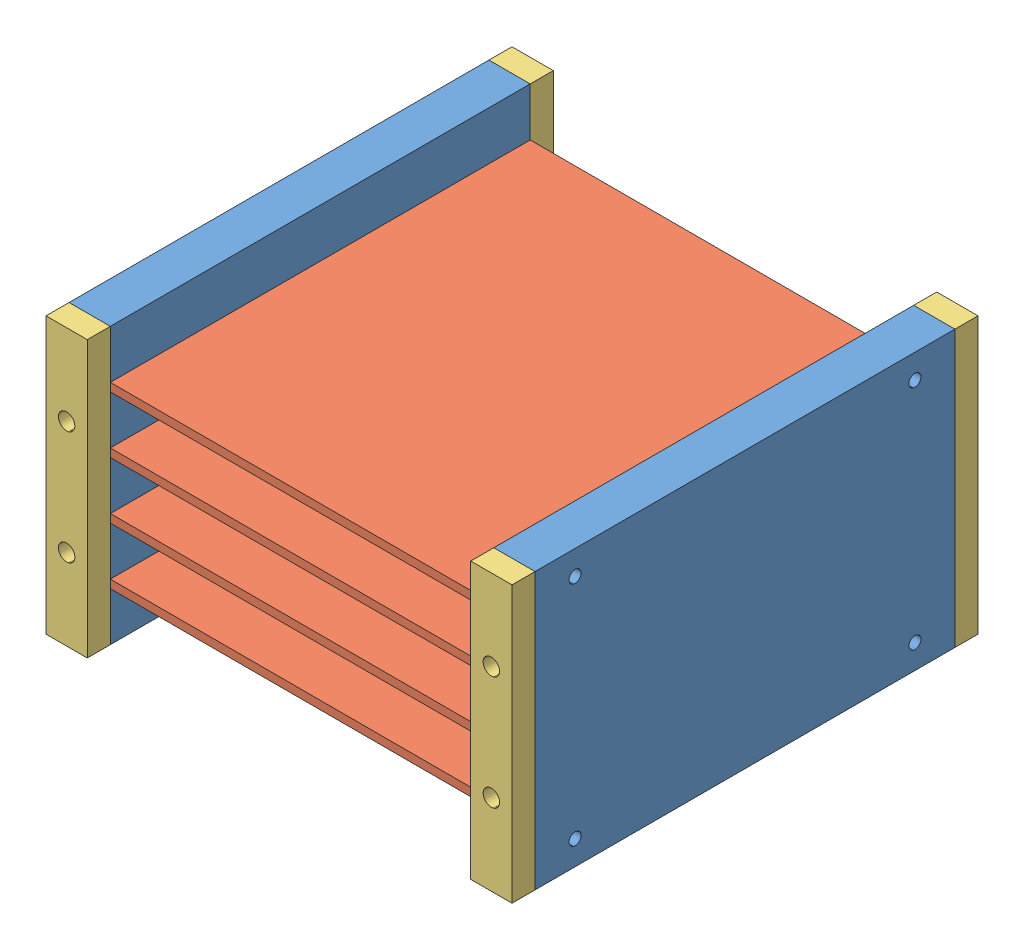
SolidWorks assembly STACK_SHELVES, configuration Default. Lengths in mm.
Overall size (96 56.8 96).
10 component instances, 3 part files, 27 mates.
Components (placement in the parent):
- PCB_SHELF-1: PCB_SHELF [Default] at (9.1658 22.2347 29.3721) size (8.5 56.8 86.5)
- FAKE_PCB-1: FAKE_PCB [Default] at (11.6658 67.3347 115.8721) size (91 1.7 86.5)
- FAKE_PCB-2: FAKE_PCB [Default] at (11.6658 55.6347 115.8721) size (91 1.7 86.5)
- FAKE_PCB-3: FAKE_PCB [Default] at (11.6658 43.9347 115.8721) size (91 1.7 86.5)
- FAKE_PCB-4: FAKE_PCB [Default] at (11.6658 32.2347 115.8721) size (91 1.7 86.5)
- PCB_SHELF-2: PCB_SHELF [Default] at (105.1658 22.2347 115.8721) x (-1 0 0) z (0 0 -1) size (8.5 56.8 86.5)
- PCB_SHELF_ENDS-1: PCB_SHELF_ENDS [Default] at (9.1658 79.0347 115.8721) size (8.5 56.8 4.75)
- PCB_SHELF_ENDS-2: PCB_SHELF_ENDS [Default] at (9.1658 79.0347 24.6221) size (8.5 56.8 4.75)
- PCB_SHELF_ENDS-3: PCB_SHELF_ENDS [Default] at (96.6658 79.0347 115.8721) size (8.5 56.8 4.75)
- PCB_SHELF_ENDS-4: PCB_SHELF_ENDS [Default] at (96.6658 79.0347 24.6221) size (8.5 56.8 4.75)
Mates (geometry in assembly coordinates):
- Coincident1: coincident anti-aligned: plane of PCB_SHELF-1 through (11.6658 69.0347 115.8721) normal (1 0 0); plane of FAKE_PCB-1 through (11.6658 69.0347 115.8721) normal (-1 0 0)
- Parallel1: parallel anti-aligned: plane of PCB_SHELF-1 through (11.6658 67.3347 115.8721) normal (0 1 0); plane of FAKE_PCB-1 through (11.6658 67.3347 115.8721) normal (0 -1 0)
- Coincident4: coincident aligned: plane of PCB_SHELF-1 through (9.1658 22.2347 115.8721) normal (0 0 1); plane of FAKE_PCB-1 through (102.6658 69.0347 115.8721) normal (0 0 1)
- Coincident5: coincident anti-aligned: plane of PCB_SHELF-1 through (11.6658 67.3347 115.8721) normal (0 1 0); plane of FAKE_PCB-1 through (11.6658 67.3347 115.8721) normal (0 -1 0)
- Coincident6: coincident anti-aligned: plane of PCB_SHELF-1 through (11.6658 57.3347 115.8721) normal (1 0 0); plane of FAKE_PCB-2 through (11.6658 57.3347 115.8721) normal (-1 0 0)
- Coincident7: coincident anti-aligned: plane of PCB_SHELF-1 through (17.6658 57.3347 115.8721) normal (0 -1 0); plane of FAKE_PCB-2 through (11.6658 57.3347 115.8721) normal (0 1 0)
- Coincident8: coincident aligned: plane of PCB_SHELF-1 through (9.1658 22.2347 115.8721) normal (0 0 1); plane of FAKE_PCB-2 through (102.6658 57.3347 115.8721) normal (0 0 1)
- Coincident9: coincident anti-aligned: plane of PCB_SHELF-1 through (11.6658 45.6347 115.8721) normal (1 0 0); plane of FAKE_PCB-3 through (11.6658 45.6347 115.8721) normal (-1 0 0)
- Coincident10: coincident anti-aligned: plane of PCB_SHELF-1 through (17.6658 45.6347 115.8721) normal (0 -1 0); plane of FAKE_PCB-3 through (11.6658 45.6347 115.8721) normal (0 1 0)
- Coincident11: coincident aligned: plane of PCB_SHELF-1 through (9.1658 22.2347 115.8721) normal (0 0 1); plane of FAKE_PCB-3 through (102.6658 45.6347 115.8721) normal (0 0 1)
- Coincident12: coincident anti-aligned: plane of PCB_SHELF-1 through (11.6658 33.9347 115.8721) normal (1 0 0); plane of FAKE_PCB-4 through (11.6658 33.9347 115.8721) normal (-1 0 0)
- Coincident13: coincident anti-aligned: plane of PCB_SHELF-1 through (17.6658 33.9347 115.8721) normal (0 -1 0); plane of FAKE_PCB-4 through (11.6658 33.9347 115.8721) normal (0 1 0)
- Coincident14: coincident aligned: plane of PCB_SHELF-1 through (9.1658 22.2347 115.8721) normal (0 0 1); plane of FAKE_PCB-4 through (102.6658 33.9347 115.8721) normal (0 0 1)
- Coincident15: coincident anti-aligned: plane of FAKE_PCB-4 through (102.6658 33.9347 29.3721) normal (1 0 0); plane of PCB_SHELF-2 through (102.6658 33.9347 29.3721) normal (-1 0 0)
- Coincident16: coincident anti-aligned: plane of FAKE_PCB-4 through (11.6658 33.9347 115.8721) normal (0 1 0); plane of PCB_SHELF-2 through (96.6658 33.9347 29.3721) normal (0 -1 0)
- Coincident17: coincident aligned: plane of FAKE_PCB-4 through (102.6658 33.9347 115.8721) normal (0 0 1); plane of PCB_SHELF-2 through (105.1658 22.2347 115.8721) normal (0 0 1)
- Coincident18: coincident aligned: plane of FAKE_PCB-3 through (102.6658 45.6347 115.8721) normal (0 0 1); plane of PCB_SHELF-2 through (105.1658 22.2347 115.8721) normal (0 0 1)
- Coincident19: coincident aligned: plane of FAKE_PCB-2 through (102.6658 57.3347 115.8721) normal (0 0 1); plane of PCB_SHELF-2 through (105.1658 22.2347 115.8721) normal (0 0 1)
- Coincident20: coincident aligned: plane of FAKE_PCB-1 through (102.6658 69.0347 115.8721) normal (0 0 1); plane of PCB_SHELF-2 through (105.1658 22.2347 115.8721) normal (0 0 1)
- Coincident21: coincident aligned: circle of PCB_SHELF-2; circle of PCB_SHELF_ENDS-3
- Coincident22: coincident aligned: circle of PCB_SHELF-2; circle of PCB_SHELF_ENDS-3
- Coincident23: coincident aligned: circle of PCB_SHELF-1; circle of PCB_SHELF_ENDS-1
- Coincident24: coincident aligned: circle of PCB_SHELF-1; circle of PCB_SHELF_ENDS-1
- Coincident25: coincident anti-aligned: circle of PCB_SHELF-2; circle of PCB_SHELF_ENDS-4
- Coincident26: coincident anti-aligned: circle of PCB_SHELF-2; circle of PCB_SHELF_ENDS-4
- Coincident27: coincident anti-aligned: circle of PCB_SHELF-1; circle of PCB_SHELF_ENDS-2
- Coincident28: coincident anti-aligned: circle of PCB_SHELF-1; circle of PCB_SHELF_ENDS-2
